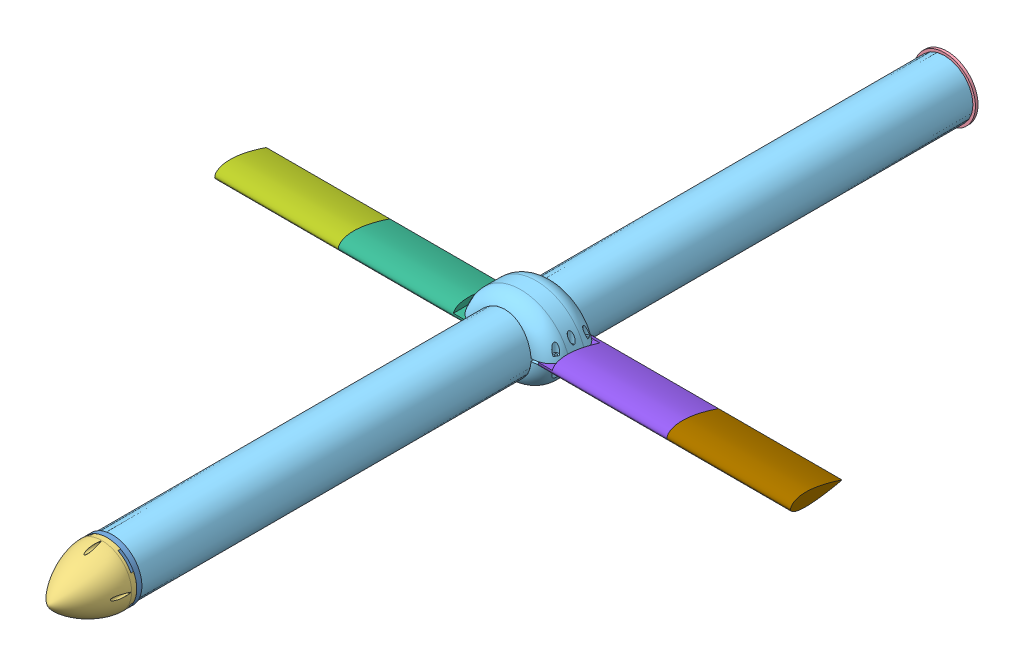
SolidWorks assembly Main_2, configuration Default. Lengths in mm.
Overall size (1118.12 192.33 1744.63).
158 component instances, 66 part files, 20 mates.
Components (placement in the parent):
- MM_Main-1: MM_Main [Default] at origin size (192.33 192.33 813)
  - MM_moving_stepper_disk-1: MM_moving_stepper_disk [Default] at (0 0 -581.4) size (100 100 5)
  - MM_NEMA_17-1: MM_NEMA_17 [Default] at (0 -2 -614.4) x (1 0 0) z (0 -1 0) size (45.3 55 42.3)
  - MM_5x5coupler-1: MM_5x5coupler [Default] at (0 -2 -541.4) x (0.507474 0.861667 0) z (0 0 -1) size (16 16 26)
  - MM_Mass_shaft2-1: MM_Mass_shaft2 [Default] at (0 -2 -549.4) x (0.265176 0.9642 0) z (0.9642 -0.265176 0) size (8 34 8)
  - MM_Mass_handle-1: MM_Mass_handle [Default] at (0 -30 -519.4) size (30 32 5)
  - MM_Mass-1: MM_Mass [Default] at (-15 -30 -519.4) size (30 10 200)
  - MM_Mass_handle-2: MM_Mass_handle [Default] at (0 -30 -314.4) size (30 32 5)
  - MM_Mass_shaft-2: MM_Mass_shaft [Default] at (0 -2 -309.4) x (-0.93094 -0.365173 0) z (-0.365173 0.93094 0) size (9.17 19 8.51)
  - MM_moving_disk-1: MM_moving_disk [Default] at (0 0 -529.4) size (100 100 5)
  - MM_moving_disk2-1: MM_moving_disk2 [Default] at (0 0 -304.5) size (100 100 5)
  - MM_shft_screw_nut-1: MM_shft_screw_nut [Default] at (0 26 -304.5) x (-1 0 0) z (0 -1 0) size (35 20 30)
  - MM_moving_construct-1: MM_moving_construct [Default] at (-29.6985 29.6985 -586.5) x (-0.109158 -0.994024 0) z (0 0 1) size (6 6 300)
  - MM_moving_construct-2: MM_moving_construct [Default] at (-29.6985 -29.6985 -586.5) x (0.994024 -0.109158 0) z (0 0 1) size (6 6 300)
  - MM_moving_construct-3: MM_moving_construct [Default] at (29.6985 -29.6985 -586.5) x (0.109158 0.994024 0) z (0 0 1) size (6 6 300)
  - MM_moving_construct-4: MM_moving_construct [Default] at (29.6985 29.6985 -586.5) x (-0.994024 0.109158 0) z (0 0 1) size (6 6 300)
  - MM_moving_fix_thread-1: MM_moving_fix_thread [Default] at (29.6985 29.6985 -576.4) x (0 -1 0) z (0 0 1) size (18 18 8)
  - MM_moving_fix_thread-2: MM_moving_fix_thread [Default] at (29.6985 29.6985 -537.4) x (0 -1 0) z (0 0 1) size (18 18 8)
  - MM_moving_fix_thread-3: MM_moving_fix_thread [Default] at (29.6985 29.6985 -299.5) x (0 1 0) z (0 0 1) size (18 18 8)
  - MM_moving_fix_thread-4: MM_moving_fix_thread [Default] at (29.6985 -29.6985 -576.4) x (-1 0 0) z (0 0 1) size (18 18 8)
  - MM_moving_fix_thread-5: MM_moving_fix_thread [Default] at (-29.6985 -29.6985 -576.4) x (0 1 0) z (0 0 1) size (18 18 8)
  - MM_moving_fix_thread-6: MM_moving_fix_thread [Default] at (-29.6985 29.6985 -576.4) size (18 18 8)
  - MM_moving_fix_thread-7: MM_moving_fix_thread [Default] at (29.6985 -29.6985 -537.4) x (-1 0 0) z (0 0 1) size (18 18 8)
  - MM_moving_fix_thread-8: MM_moving_fix_thread [Default] at (-29.6985 -29.6985 -537.4) x (0 1 0) z (0 0 1) size (18 18 8)
  - MM_moving_fix_thread-9: MM_moving_fix_thread [Default] at (-29.6985 29.6985 -537.4) size (18 18 8)
  - MM_moving_fix_thread-10: MM_moving_fix_thread [Default] at (29.6985 -29.6985 -299.5) size (18 18 8)
  - MM_moving_fix_thread-11: MM_moving_fix_thread [Default] at (-29.6985 -29.6985 -299.5) x (0 -1 0) z (0 0 1) size (18 18 8)
  - MM_moving_fix_thread-12: MM_moving_fix_thread [Default] at (-29.6985 29.6985 -299.5) x (-1 0 0) z (0 0 1) size (18 18 8)
  - MM_static2.2-1: MM_static2.2 [Default] at (0 0 -171) size (100 100 5)
  - MM_static_stepper-1: MM_static_stepper [Default] at (0 0 -118) size (100 100 5)
  - MM_NEMA_17-2: MM_NEMA_17 [Default] at (0 26 -80) x (-1 0 0) z (0 -1 0) size (45.3 55 42.3)
  - MM_5x5coupler-2: MM_5x5coupler [Default] at (0 26 -153) x (-0.062572 0.99804 0) z (0 0 1) size (16 16 26)
  - MM_shaft_extend-2: MM_shaft_extend [Default] at (0 26 -145) x (-0.999277 -0.038026 0) z (0 0 -1) size (8 8 41)
  - MM_shaft-2: MM_shaft [Default] at (0 26 -536) x (0.038026 -0.999277 0) z (0 0 1) size (8 8 360)
  - MM_shaft_extend_long -1: MM_shaft_extend_long  [Default] at (0 26 -756) x (0.999277 0.038026 0) z (0 0 1) size (8 8 230)
  - MM_static2.2-2: MM_static2.2 [Default] at (0 0 -733) size (100 100 5)
  - MM_construct-1: MM_construct [Default] at (-37 0 -775.5) x (0.04747 0.998873 0) z (0 0 1) size (10 10 733)
  - MM_fix-1: MM_fix [Default] at (-37 0 -179) x (0.99297 0.118365 0) z (0 0 1) size (24 24 8)
  - MM_fix-2: MM_fix [Default] at (-37 0 -126) size (24 24 8)
  - MM_fix-3: MM_fix [Default] at (-37 0 -741) size (24 24 8)
  - MM_fix-4: MM_fix [Default] at (37 0 -733) x (-1 0 0) z (0 0 -1) size (24 24 8)
  - MM_construct-2: MM_construct [Default] at (37 0 -42.5) x (-0.04747 0.998873 0) z (0 0 -1) size (10 10 733)
  - MM_fix-5: MM_fix [Default] at (37 0 -171) x (-0.99297 0.118365 0) z (0 0 -1) size (24 24 8)
  - MM_fix-6: MM_fix [Default] at (37 0 -118) x (-1 0 0) z (0 0 -1) size (24 24 8)
  - MM_construct-3: MM_construct [Default] at (0 -40 -775.5) x (0.99877 -0.049577 0) z (0 0 1) size (10 10 733)
  - MM_fix-7: MM_fix [Default] at (0 -40 -179) x (0.999988 0.004807 0) z (0 0 1) size (24 24 8)
  - MM_fix-8: MM_fix [Default] at (0 -40 -126) x (0.999988 0.004807 0) z (0 0 1) size (24 24 8)
  - MM_fix-9: MM_fix [Default] at (0 -40 -741) x (0.999988 0.004807 0) z (0 0 1) size (24 24 8)
  - SE_mid_flange -1: SE_mid_flange  [Default] at (0 0 -10) x (-1 0 0) z (0 0 -1) size (106 106 50)
  - SE_end_flange  - Copy-1: SE_end_flange  - Copy [Default] at (0 0 -808) size (106 106 50)
  - SE_head3-1: SE_head3 [Default] at (0 0 -813) size (120 120 5)
  - SE_cylinder-1: SE_cylinder [Default] at (0 0 -808) size (110.4 110.4 798)
  - SE_head2.2-1: SE_head2.2 [Default] at (0 0 -10) x (0.707107 -0.707107 0) z (0 0 1) size (136 136 10)
  - o-rings ai-1: o-rings ai [AS568 - 241] at (0 0 -794.9393) x (1 0 0) z (0 -1 0) size (105.08 3.53 105.08) (hidden)
  - o-rings ai-2: o-rings ai [AS568 - 343] at (0 0 -783.6274) x (1 0 0) z (0 1 0) size (105.28 5.33 105.28) (hidden)
  - o-rings ai-3: o-rings ai [AS568 - 224] at (0 0 -807.0983) x (-1 0 0) z (0 -1 0) size (51.1 3.53 51.1) (hidden)
  - o-rings ai-7: o-rings ai [AS568 - 045] at (0 0 -808.5588) x (1 0 0) z (0 1 0) size (104.37 1.52 104.37) (hidden)
  - angular contact ball bearing_68_iso-1: angular contact ball bearing_68_iso [ISO 15 ABB - 196 - 10,SI,NC,10_68] at (0 -2 -302) x (0 0 -1) z (1 0 0) size (5 15 15)
  - angular contact ball bearing_68_iso-2: angular contact ball bearing_68_iso [ISO 15 ABB - 196 - 10,SI,NC,10_68] at (0 26 -168.5) x (0 0 -1) z (1 0 0) size (5 15 15)
  - angular contact ball bearing_68_iso-3: angular contact ball bearing_68_iso [ISO 15 ABB - 196 - 10,SI,NC,10_68] at (0 26 -730.5) x (0 0 -1) z (1 0 0) size (5 15 15)
  - angular contact ball bearing_68_iso-4: angular contact ball bearing_68_iso [ISO 15 ABB - 196 - 10,SI,NC,10_68] at (0 -2 -526.9) x (0 0 -1) z (1 0 0) size (5 15 15)
  - MM_smooth-1: MM_smooth [Default] at (-37 0 -581.4) size (26 26 6)
  - MM_smooth-2: MM_smooth [Default] at (37 0 -581.4) size (26 26 6)
  - MM_smooth-4: MM_smooth [Default] at (37 0 -529.4) size (26 26 6)
  - MM_smooth-6: MM_smooth [Default] at (-37 0 -529.4) size (26 26 6)
  - MM_smooth-8: MM_smooth [Default] at (37 0 -304.5) size (26 26 6)
  - MM_smooth-9: MM_smooth [Default] at (-37 0 -304.5) size (26 26 6)
- BE_MAIN-1: BE_MAIN [Default] at origin size (192.33 192.33 966.63)
  - BE_stepper_disk-1: BE_stepper_disk [Default] at (0 0 319) size (100 100 5)
  - NEMA17_double-1: NEMA17_double [Default] at (0 0 275) size (42.3 42.3 68)
  - BE_5x5coupler-1: BE_5x5coupler [Default] at (0 0 332) x (-0.02125 -0.999774 0) z (0 0 1) size (16 16 26)
  - BE_construct-1: BE_construct [Default] at (-37 0 42.5) x (0.279268 -0.960213 0) z (0 0 1) size (10 10 733)
  - BE_fix_thread-1: BE_fix_thread [Default] at (-37 0 324) size (24 24 8)
  - BE_TH-1: BE_TH [Default] at (0 0 348) x (-0.975003 0.222193 0) z (0 0 1) size (8 8 41)
  - angular contact ball bearing_68_iso-1: angular contact ball bearing_68_iso [ISO 15 ABB - 196 - 10,SI,NC,10_68] at (0 0 371.5) x (0 0 1) z (-0.923728 -0.383049 0) size (5 15 15)
  - BE_static_1-1: BE_static_1 [Default] at (0 0 369) size (100 100 5)
  - BE_shaft-1: BE_shaft [Default] at (0 0 689) x (0.222193 0.975003 0) z (0 0 -1) size (8 8 310)
  - BE_fix_thread-2: BE_fix_thread [Default] at (-37 0 374) size (24 24 8)
  - syringe piston-1: syringe piston [Default] at (24.0416 -24.0416 638) x (1 0 0) z (0 1 0) size (31 153 31)
  - BE_moving_1-1: BE_moving_1 [Default] at (0 0 487) size (100 100 5)
  - BE_nut-1: BE_nut [Default] at (0 0 487) x (-1 0 0) z (0 -1 0) size (35 47 35)
  - syringe piston-2: syringe piston [Default] at (-24.0416 -24.0416 638) x (-1 0 0) z (0 -1 0) size (31 153 31)
  - syringe piston-3: syringe piston [Default] at (0 34 638) x (1 0 0) z (0 1 0) size (31 153 31)
  - BE_smooth-1: BE_smooth [Default] at (-37 0 492) x (1 0 0) z (0 0 -1) size (26 26 6)
  - BE_smooth-2: BE_smooth [Default] at (37 0 492) x (1 0 0) z (0 0 -1) size (26 26 6)
  - BE_static_2-1: BE_static_2 [Default] at (0 0 559) size (100 100 5)
  - syringe cylinder-1: syringe cylinder [Default] at (0 34 564) x (0 -1 0) z (-1 0 0) size (40 174.01 33)
  - syringe cylinder-2: syringe cylinder [Default] at (24.0416 -24.0416 564) x (-0.707107 0.707107 0) z (0.707107 0.707107 0) size (40 174.01 33)
  - syringe cylinder-3: syringe cylinder [Default] at (-24.0416 -24.0416 564) x (0.707107 0.707107 0) z (0.707107 -0.707107 0) size (40 174.01 33)
  - BE_static_3-1: BE_static_3 [Default] at (0 0 566) size (100 100 5)
  - BE_static_4-1: BE_static_4 [Default] at (0 0 681) size (100 100 5)
  - BE_fix_thread-4: BE_fix_thread [Default] at (-37 0 571) size (24 24 8)
  - BE_fix_thread-5: BE_fix_thread [Default] at (-37 0 686) x (-0.998637 -0.052202 0) z (0 0 1) size (24 24 8)
  - BE_construct-2: BE_construct [Default] at (37 0 775.5) x (-0.279268 -0.960213 0) z (0 0 -1) size (10 10 733)
  - BE_fix_thread-10: BE_fix_thread [Default] at (0 -40 374) x (-0.978915 -0.204267 0) z (0 0 1) size (24 24 8)
  - BE_fix_thread-11: BE_fix_thread [Default] at (0 -40 571) x (0.884763 -0.466042 0) z (0 0 1) size (24 24 8)
  - BE_construct-3: BE_construct [Default] at (0 -40 42.5) x (-0.256806 -0.966463 0) z (0 0 1) size (10 10 733)
  - BE_fix_thread-12: BE_fix_thread [Default] at (0 -40 324) size (24 24 8)
  - BE_fix_thread-13: BE_fix_thread [Default] at (0 -40 686) x (-0.95349 0.301426 0) z (0 0 1) size (24 24 8)
  - CU_BeagleBoneBlue-1: CU_BeagleBoneBlue [Default] at (27.305 27.5 169.355) x (0 0 1) z (0 1 0) size (89.52 54.61 17.1)
  - CU_static-1: CU_static [Default] at (0 0 265) size (100 98.97 5)
  - CU_BBbase-1: CU_BBbase [Default] at (0 22.5 175) x (-1 0 0) z (0 0 -1) size (70 5 192)
  - CU_static-2: CU_static [Default] at (0 0 80) size (100 98.97 5)
  - BE_fix_thread-16: BE_fix_thread [Default] at (0 -40 270) size (24 24 8)
  - BE_fix_thread-17: BE_fix_thread [Default] at (-37 0 270) x (-1 0 0) z (0 0 1) size (24 24 8)
  - BE_fix_thread-18: BE_fix_thread [Default] at (-37 0 72) size (24 24 8)
  - BE_fix_thread-20: BE_fix_thread [Default] at (0 -40 72) size (24 24 8)
  - CU_BatteryBase-1: CU_BatteryBase [Default] at (0 -31.5 175) size (70 5 192)
  - CU_BatteryCase-1: CU_BatteryCase [Default] at (0 -26.5 111.9695) x (1 0 0) z (0 1 0) size (74.93 39.88 18.03)
  - CU_BatteryCase-2: CU_BatteryCase [Default] at (0 -26.5 153.9695) x (1 0 0) z (0 1 0) size (74.93 39.88 18.03)
  - CU_BatteryCase-3: CU_BatteryCase [Default] at (0 -26.5 195.9695) x (1 0 0) z (0 1 0) size (74.93 39.88 18.03)
  - CU_BatteryCase-4: CU_BatteryCase [Default] at (0 -26.5 237.9695) x (1 0 0) z (0 1 0) size (74.93 39.88 18.03)
  - CE_board-1: CE_board [Default] at (0 28.5 122.4162) x (-1 0 0) z (0 -1 0) size (69.6 70 1)
  - CE_battery-1: CE_battery [Default] at (32.5 -16.466 247.939) x (0 0 1) z (-1 0 0) size (18 18 65)
  - CE_battery-2: CE_battery [Default] at (32.5 -16.466 228) x (0 0.980747 0.195284) z (-1 0 0) size (18 18 65)
  - CE_battery-3: CE_battery [Default] at (32.5 -16.466 144) x (0 0 1) z (-1 0 0) size (18 18 65)
  - CE_battery-4: CE_battery [Default] at (32.5 -16.466 186) x (0 0 1) z (-1 0 0) size (18 18 65)
  - CE_battery-5: CE_battery [Default] at (32.5 -16.466 102) x (0 0 1) z (-1 0 0) size (18 18 65)
  - CE_battery-6: CE_battery [Default] at (32.5 -16.466 163.939) x (0 0 1) z (-1 0 0) size (18 18 65)
  - CE_battery-7: CE_battery [Default] at (32.5 -16.466 205.939) x (0 -0.788159 -0.615472) z (-1 0 0) size (18 18 65)
  - CE_battery-8: CE_battery [Default] at (32.5 -16.466 121.939) x (0 0 1) z (-1 0 0) size (18 18 65)
  - SE_One_flange-1: SE_One_flange [Default] at (0 0 808) x (-1 0 0) z (0 0 -1) size (106 106 50)
  - SE_tube1-1: SE_tube1 [Default] at (-24.0416 -24.0416 738) x (0 0 1) z (0 1 0) size (100 22.44 43.65)
  - SE_tube1-3: SE_tube1 [Default] at (24.0416 -24.0416 738) x (0 0 1) z (-0.674149 0.738595 0) size (100 22.44 43.65)
  - SE_tube2-1: SE_tube2 [Default] at (0 34 738) x (0 0 1) z (1 0 0) size (100 58 9)
  - o-rings ai-1: o-rings ai [AS568 - 241] at (0 0 795.5) x (1 0 0) z (0 -1 0) size (105.08 3.53 105.08)
  - o-rings ai-2: o-rings ai [AS568 - 343] at (0 0 785) x (1 0 0) z (0 1 0) size (105.28 5.33 105.28)
  - SE_cylinder-2: SE_cylinder [Default] at (0 0 10) size (110.4 110.4 798)
  - SE_mid_flange -1: SE_mid_flange  [Default] at (0 0 10) size (106 106 50)
  - SE_head2-1: SE_head2 [Default] x (0.707107 -0.707107 0) z (0 0 1) size (136 136 10)
  - SE_head1-2: SE_head1 [Default] at (0 0 808) size (115 115 10)
  - o-rings ai-4: o-rings ai [AS568 - 224] at (0 0 807.0983) x (0 1 0) z (-1 0 0) size (51.1 3.53 51.1)
  - o-rings ai-6: o-rings ai [AS568 - 241] at (0 0 22.5) x (1 0 0) z (0 1 0) size (105.08 3.53 105.08) (hidden)
  - o-rings ai-7: o-rings ai [AS568 - 343] at (0 0 33) x (1 0 0) z (0 -1 0) size (105.28 5.33 105.28) (hidden)
  - o-rings ai-8: o-rings ai [AS568 - 224] at (0 0 10.9017) x (0 1 0) z (1 0 0) size (51.1 3.53 51.1) (hidden)
  - o-rings ai-10: o-rings ai [AS568 - 224] at (0 0 5.9017) x (0 1 0) z (1 0 0) size (51.1 3.53 51.1) (hidden)
  - BE_fix_thread-21: BE_fix_thread [Default] at (37 0 332) x (-1 0 0) z (0 0 -1) size (24 24 8)
  - BE_fix_thread-22: BE_fix_thread [Default] at (37 0 80) x (-1 0 0) z (0 0 -1) size (24 24 8)
  - BE_fix_thread-23: BE_fix_thread [Default] at (37 0 278) x (1 0 0) z (0 0 -1) size (24 24 8)
  - BE_fix_thread-24: BE_fix_thread [Default] at (37 0 382) x (-1 0 0) z (0 0 -1) size (24 24 8)
  - BE_fix_thread-25: BE_fix_thread [Default] at (37 0 579) x (-1 0 0) z (0 0 -1) size (24 24 8)
  - BE_fix_thread-26: BE_fix_thread [Default] at (37 0 694) x (0.998637 -0.052202 0) z (0 0 -1) size (24 24 8)
  - angular contact ball bearing_68_iso-3: angular contact ball bearing_68_iso [ISO 15 ABB - 196 - 10,SI,NC,10_68] at (0 0 683.5) x (0 0 1) z (-0.923728 -0.383049 0) size (5 15 15)
  - middle2-1: middle2 [Default] x (0.707107 0.707107 0) z (0 0 1) size (50 50 75)
  - head-1: head [Default] at (0 0 828) x (1 0 0) z (0 -1 0) size (115 113.63 115)
  - water pipe-1: water pipe [Default] at (37.0416 -24.0416 696) x (0 0 -1) z (1 0 0) size (58 26 26)
  - water pipe-2: water pipe [Default] at (-11.0416 -24.0416 696) x (0 0 -1) z (1 0 0) size (58 26 26)
  - water pipe-3: water pipe [Default] at (12.9742 33.1816 696) x (0 0 -1) z (0.998016 -0.062956 0) size (58 26 26)
- Wing_Assembly-1: Wing_Assembly [Default] at (0 0 50) x (-1 0 0) z (0 0 -1) size (1118.12 146 106.33)
  - fixWings2 -1: fixWings2  [Default] at origin size (193.16 70.5 106.33)
  - fixWings2 -2: fixWings2  [Default] at (0 0 100) x (1 0 0) z (0 0 -1) size (193.16 70.5 106.33)
  - Wing1_1-1: Wing1_1 [Default] at (194.0625 0 0) x (0 0 1) z (-1 0 0) size (100 25.05 250)
  - Wing1_2-1: Wing1_2 [Default] at (434.0625 0 0) x (0 0 1) z (-1 0 0) size (100 25.05 250)
  - Wing2_1-1: Wing2_1 [Default] at (-194.0625 0 -0.0002) x (0 0 1) z (-1 0 0) size (100 25.05 250)
  - Wing2_2-1: Wing2_2 [Default] at (-434.0625 0 -0.0002) x (0 0 1) z (-1 0 0) size (100 25.05 250)
- masses-1: masses [Default] at (0 0 -757.4164) size (104 103.76 15)
- masses2-1: masses2 [Default] at (0 0 706) size (104 103.59 25)
- masses3-4: masses3 [Default] at (0 0 60) size (104 103.76 10)
Mates (geometry in assembly coordinates):
- Concentric1: concentric anti-aligned: cylinder of MM_Main-1/SE_head2.2-1 through (0 0 -10) axis (0 0 1) radius 68; cylinder of BE_MAIN-1/SE_head2-1 through (0 0 10) axis (0 0 -1) radius 68
- Coincident1: coincident anti-aligned: plane of MM_Main-1/SE_head2.2-1 through (0 0 0) normal (0 0 1); plane of BE_MAIN-1/SE_head2-1 through (0 0 0) normal (0 0 -1)
- Coincident2: coincident aligned: plane of MM_Main-1 through (0 0 0) normal (0 1 0); plane of BE_MAIN-1 through (0 0 0) normal (0 1 0)
- Coincident4: coincident: unknown of BE_MAIN-1/SE_head2-1
- Parallel1: parallel aligned: plane of MM_Main-1/MM_NEMA_17-2 through (-16 46 -90.5) normal (0 1 0); plane of assembly through (0 0 0) normal (0 1 0)
- Parallel2: parallel anti-aligned: plane of MM_Main-1/MM_NEMA_17-2 through (-20 42 -90.5) normal (-1 0 0); plane of assembly through (0 0 0) normal (1 0 0)
- Parallel3: parallel: plane of ? through (96.0625 2.5 50.0002) normal (0 1 0); plane of assembly through (0 0 0) normal (0 1 0)
- Parallel4: parallel: plane of ? through (569.0625 -8.8726 1.4573) normal (1 0 0); plane of assembly through (0 0 0) normal (1 0 0)
- Concentric3: concentric aligned: cylinder of BE_MAIN-1/SE_cylinder-2 through (0 0 808) axis (0 0 -1) radius 55.2; cylinder of Wing_Assembly-1/fixWings2 -2 through (0 0 171.4189) axis (0 0 -1) radius 55
- Distance1: distance = 40 mm: line of ? through (-69.0625 0 50) axis (-1 0 0); plane of BE_MAIN-1/SE_head2-1 through (0 0 10) normal (0 0 1)
- Concentric4: concentric aligned: cylinder of MM_Main-1/SE_end_flange  - Copy-1 through (0 0 -758) axis (0 0 -1) radius 53; cylinder of masses-1 through (0 0 -742.4164) axis (0 0 -1) radius 52
- Tangent1: tangent anti-aligned: cylinder of MM_Main-1/MM_construct-2 through (37 0 -775.5) axis (0 0 1) radius 5; plane of masses-1 through (32 0 -757.4164) normal (1 0 0)
- Concentric6: concentric anti-aligned: cylinder of BE_MAIN-1/SE_One_flange-1 through (0 0 758) axis (0 0 1) radius 53; cylinder of masses2-1 through (0 0 731) axis (0 0 -1) radius 52
- Tangent3: tangent anti-aligned: cylinder of BE_MAIN-1/BE_construct-2 through (37 0 42.5) axis (0 0 1) radius 5; plane of masses2-1 through (32 0 706) normal (1 0 0)
- Distance2: distance = 20 mm anti-aligned: plane of masses2-1 through (0 0 706) normal (0 0 -1); plane of BE_MAIN-1/BE_static_4-1 through (0 0 686) normal (0 0 1)
- Concentric7: concentric aligned: cylinder of BE_MAIN-1/SE_mid_flange -1 through (0 0 60) axis (0 0 -1) radius 53; cylinder of masses3-4 through (0 0 70) axis (0 0 -1) radius 52
- Tangent4: tangent anti-aligned: cylinder of BE_MAIN-1/BE_construct-2 through (37 0 42.5) axis (0 0 1) radius 5; plane of masses3-4 through (32 0 60) normal (1 0 0)
- Coincident8: coincident anti-aligned: plane of BE_MAIN-1/SE_mid_flange -1 through (0 0 60) normal (0 0 1); plane of masses3-4 through (0 0 60) normal (0 0 -1)
- Coincident9: coincident aligned: plane of Wing_Assembly-1 through (0 0 171.4189) normal (0 1 0)
- Distance4: distance = 50 mm: plane of Wing_Assembly-1 through (0 0 50) normal (0 0 -1)
